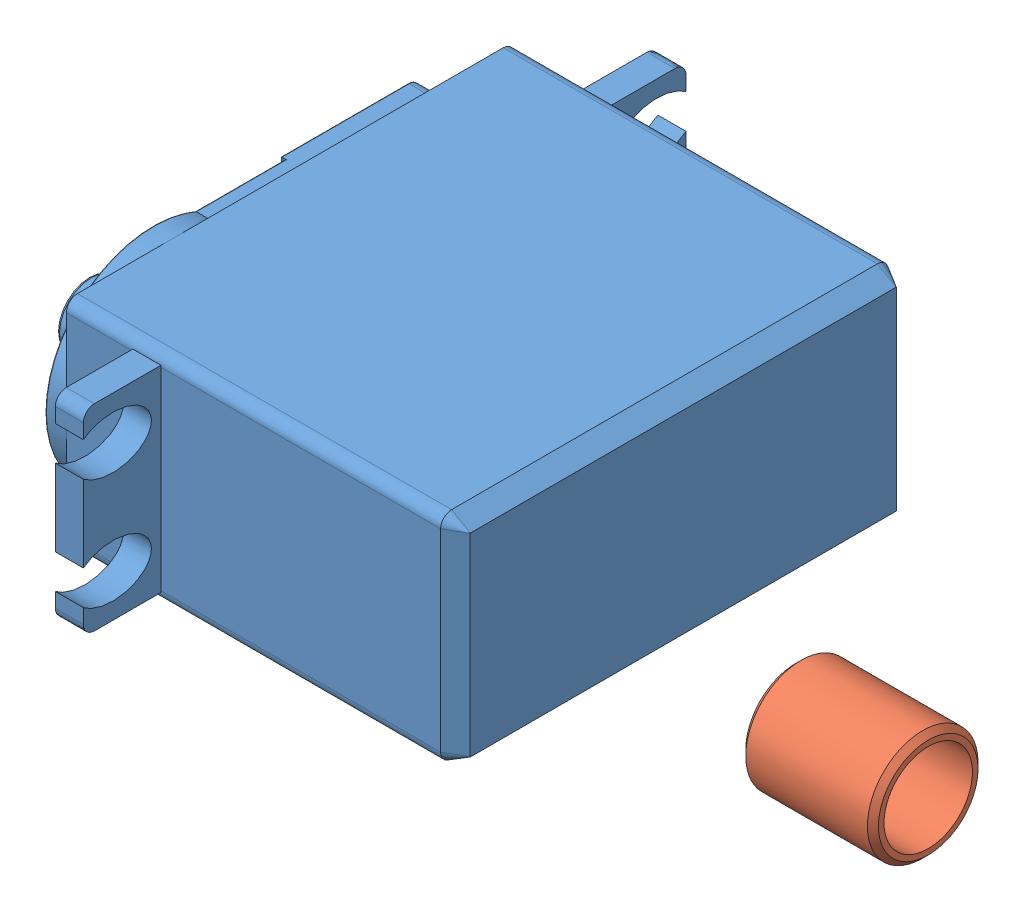
SolidWorks assembly AssemblyForearm, configuration По умолчанию. Lengths in mm.
Overall size (75.84 19.5 54.5).
4 component instances, 4 part files, 6 mates.
Components (placement in the parent):
- Forearm1-1: Forearm1 [По умолчанию] at (-12 139.75 -0.0004) x (0 -1 0) z (-1 0 0) (suppressed, hidden)
- MG995-1: MG995 [預設] at (-20 129.75 49.2496) x (0 0 1) z (0 -1 0) size (54.5 43.19 19.5)
- Forearm2-1: Forearm2 [По умолчанию] at (39.65 139.75 0) x (0 -0.999995 -0.003125) z (-1 0 0) (suppressed, hidden)
- sleeve-1: sleeve [По умолчанию] at (27.65 139.5 79.9996) x (0 0 -1) z (1 0 0) size (10 10 12)
Mates (geometry in assembly coordinates):
- Совпадение19: coincident anti-aligned: plane of Forearm1-1 through (-20 139.75 -0.0004) normal (-1 0 0); plane of MG995-1 through (-20 129.75 49.2496) normal (1 0 0)
- Совпадение20: coincident anti-aligned: plane of Forearm1-1 through (-20 129.75 -0.0004) normal (0 1 0); plane of MG995-1 through (-28.54 129.75 49.2496) normal (0 -1 0)
- Совпадение21: coincident anti-aligned: plane of Forearm1-1 through (-20 139.75 89.7496) normal (0 0 -1); plane of MG995-1 through (-28.54 129.75 89.7496) normal (0 0 1)
- Концентричный11: concentric aligned: cylinder of MG995-1 through (-36.19 139.5 79.9996) axis (1 0 0) radius 2.925; cylinder of Forearm2-1 through (27.65 139.5 79.9996) axis (1 0 0) radius 5.15
- Концентричный13: concentric anti-aligned: cylinder of Forearm2-1 through (27.65 139.5 79.9996) axis (1 0 0) radius 5.15; cylinder of sleeve-1 through (39.65 139.5 79.9996) axis (-1 0 0) radius 5
- Совпадение33: coincident aligned: plane of Forearm2-1 through (39.65 139.75 0) normal (1 0 0); plane of sleeve-1 through (39.65 139.5 79.9996) normal (1 0 0)
